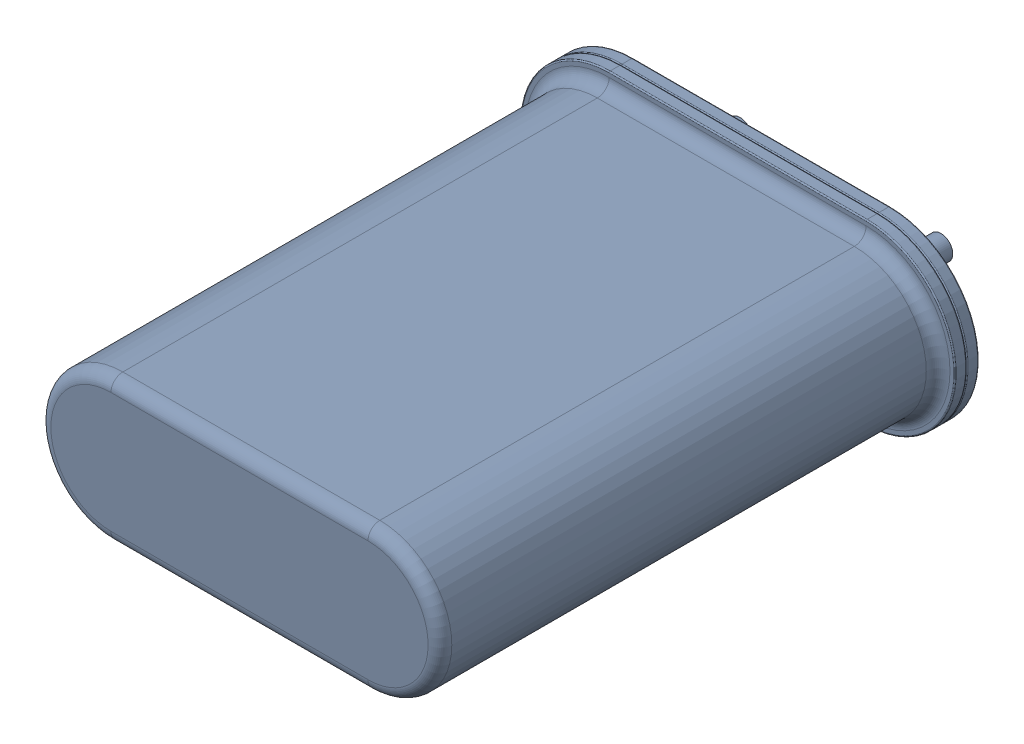
SolidWorks assembly X1, configuration Défaut. Lengths in mm.
Overall size (11 4.5 15.2).
2 component instances, 1 part files, 0 mates.
Components (placement in the parent):
- Open CASCADE STEP translator 6.8 1.5.1-1: Open CASCADE STEP translator 6.8 1.5.1 [Défaut] at origin size (11 4.5 15.2)
  - Body_1_4-1: Body_1_4 [Défaut] at (2.5 0 0) x (1 0 0) z (0 -1 0) size (11 15.2 4.5)
